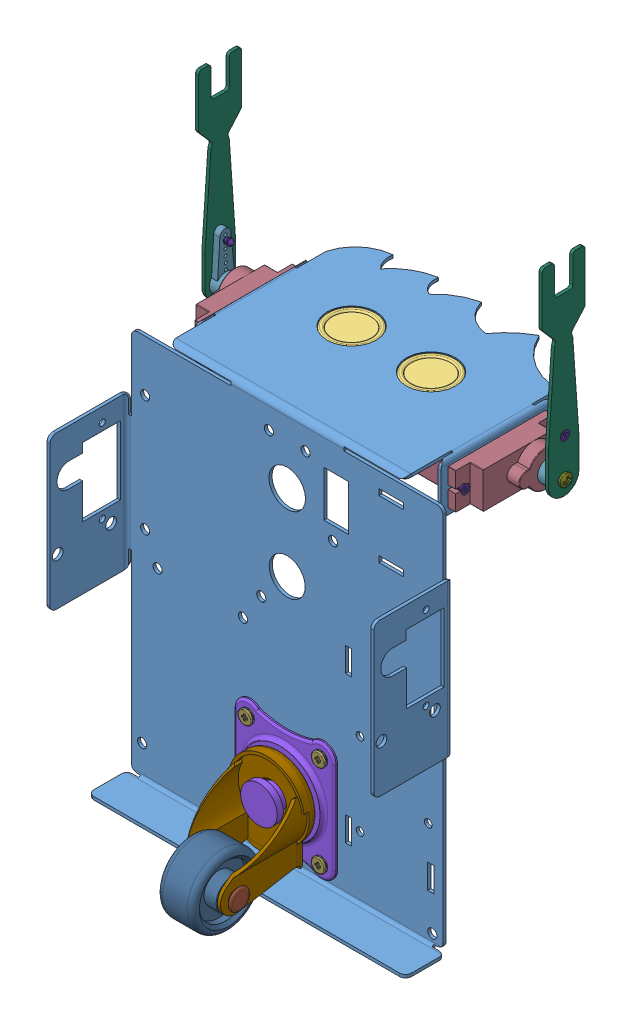
SolidWorks assembly MS_AR, configuration Predeterminado. Lengths in mm.
Overall size (116.68 188.48 99.79).
42 component instances, 17 part files, 13 mates.
Components (placement in the parent):
- DYOR_MetalSheet_Arms-1: DYOR_MetalSheet_Arms [Predeterminado] at (11.469 -59.0071 139.7994) size (107.01 129.17 87.35)
- HC-SR04 Ping Sensor-1: HC-SR04 Ping Sensor [Default] at (150.9644 -203.1957 105.6113) x (0 0 -1) z (0 1 0) size (25.18 45 18.07)
  - PCB-1: PCB [Default] at origin size (20.5 45 1.75)
  - Transducer-1: Transducer [Default] at (0 -13 13.25) x (1 0 0) z (0 -1 0) size (15.88 12 15.88)
  - Transducer-2: Transducer [Default] at (0 13 13.25) x (1 0 0) z (0 -1 0) size (15.88 12 15.88)
  - 3 Pin Header 90 Degree-1: 3 Pin Header 90 Degree [Default] at (8.4275 0 -1.25) x (-1 0 0) z (0 -1 0) size (8 7.82 10)
  - 14 Pin SMT-1: 14 Pin SMT [Default] at (-0.35 -18.5 -0.85) x (0 -1 0) z (1 0 0) size (6 1.6 8.8)
  - 14 Pin SMT-2: 14 Pin SMT [Default] at (0 -0.3826 -0.85) x (1 0 0) z (0 1 0) size (6 1.6 8.8)
  - 14 Pin SMT-3: 14 Pin SMT [Default] at (0 17.5274 -0.85) x (1 0 0) z (0 1 0) size (6 1.6 8.8)
  - Cap1 SMT-1: Cap1 SMT [Default] at (-1.755 7.4774 -0.9689) x (0 1 0) z (-1 0 0) size (4.5 1.84 1.75)
  - Cap1 SMT-2: Cap1 SMT [Default] at (6.835 7.4774 -0.9689) x (0 1 0) z (-1 0 0) size (4.5 1.84 1.75)
  - Cap1 SMT-3: Cap1 SMT [Default] at (-6.835 7.4774 -0.9689) x (0 1 0) z (-1 0 0) size (4.5 1.84 1.75)
  - Cap1 SMT-4: Cap1 SMT [Default] at (4.295 7.4774 -0.9689) x (0 1 0) z (-1 0 0) size (4.5 1.84 1.75)
  - Cap1 SMT-5: Cap1 SMT [Default] at (1.755 7.4774 -0.9689) x (0 1 0) z (-1 0 0) size (4.5 1.84 1.75)
  - Cap1 SMT-6: Cap1 SMT [Default] at (-4.295 7.4774 -0.9689) x (0 1 0) z (-1 0 0) size (4.5 1.84 1.75)
  - HC-SR04 Crystal-1: HC-SR04 Crystal [Default] at (-8.3 0 1.75) x (0 -1 0) z (0 0 1) size (10 3.5 2.7)
- CA-1: CA [Predeterminado] at (2.8545 2.6133 1.124) size (33 45.94 42.59)
  - Caster Wheel-1: Caster Wheel [Default] at (194.2283 -297.83 183.8938) x (0 1 0) z (-1 0 0) size (45.94 37.59 33)
    - caster holder-1: caster holder [Default] at (-24.0751 44.7184 29.5137) x (1 0 0) z (0 0 -1) size (39 9.27 33)
    - holder-1: holder [Default] at (-1.5751 42.9484 46.0137) x (0 0 1) z (1 0 0) size (25 28.07 31.31)
    - caster wheel-1: caster wheel [Default] at (-15.6961 19.9484 46.0137) x (0.997275 0.073773 0) z (0 0 1) size (23 23 14)
    - Part4-1: Part4 [Default] at (-15.6961 19.9484 55.0137) x (-0.978448 0.206495 0) z (0 0 -1) size (7 7 20)
  - M3x6 SelfTap Screw-1: M3x6 SelfTap Screw [Predeterminado] at (136.2146 -284.4051 140.6754) size (4.62 4.62 7)
  - M3x6 SelfTap Screw-2: M3x6 SelfTap Screw [Predeterminado] at (136.2146 -314.4051 140.6754) size (4.62 4.62 7)
  - M3x6 SelfTap Screw-3: M3x6 SelfTap Screw [Predeterminado] at (160.2146 -284.4051 140.6754) size (4.62 4.62 7)
  - M3x6 SelfTap Screw-4: M3x6 SelfTap Screw [Predeterminado] at (160.2146 -314.4051 140.6754) size (4.62 4.62 7)
- AR2-1: AR2 [Predeterminado] at (0 1.3678 1.1897) size (34.06 68.75 31.9)
  - sg90-1: sg90 [Default] at (175.3764 -204.8635 98.9775) x (0 0 1) z (0 1 0) size (31.9 29.9 11.8)
  - SG90 plastic Horn-1: SG90 plastic Horn [Default] at (204.8264 -198.9635 104.8775) x (0 0.999858 0.016879) z (0 0.016879 -0.999858) size (19.4 4 7.07)
  - Arm-1: Arm [Predeterminado] at (207.8264 -183.2019 150.0835) x (0 0 -1) z (1 0 0) size (14 67.85 1)
  - (M2_3_mm)_90116A007_METRIC 316 SS PAN HEAD PHILLIPS MACHINE SCREW-1: (M2_3_mm)_90116A007_METRIC 316 SS PAN HEAD PHILLIPS MACHINE SCREW [90116A007] at (204.8264 -198.9635 104.8775) x (0 0 -1) z (1 0 0) size (4 4 4.68)
  - M2x6 SelfTap Screw-2: M2x6 SelfTap Screw [Predeterminado] at (208.3264 -186.4635 104.8775) x (0 -0.924225 -0.381849) z (1 0 0) size (3.4 3.28 6)
  - M2x6 SelfTap Screw-4: M2x6 SelfTap Screw [Predeterminado] at (194.7764 -198.9635 123.8775) x (0 -0.924225 -0.381849) z (1 0 0) size (3.4 3.28 6)
  - M2x6 SelfTap Screw-6: M2x6 SelfTap Screw [Predeterminado] at (194.7764 -198.9635 96.5775) x (0 -0.924225 -0.381849) z (1 0 0) size (3.4 3.28 6)
- AR1-1: AR1 [Predeterminado] at (0 1.3678 1.1897) size (34.06 68.75 31.9)
  - sg90-2: sg90 [Default] at (126.818 -193.0635 98.9775) x (0 0 1) z (0 -1 0) size (31.9 29.9 11.8)
  - SG90 plastic Horn-2: SG90 plastic Horn [Default] at (97.368 -198.9635 104.8775) x (0 0.999767 0.021606) z (0 -0.021606 0.999767) size (19.4 4 7.07)
  - Arm-2: Arm [Predeterminado] at (94.368 -183.2019 59.6715) x (0 0 1) z (-1 0 0) size (14 67.85 1)
  - (M2_3_mm)_90116A007_METRIC 316 SS PAN HEAD PHILLIPS MACHINE SCREW-2: (M2_3_mm)_90116A007_METRIC 316 SS PAN HEAD PHILLIPS MACHINE SCREW [90116A007] at (97.368 -198.9635 104.8775) x (0 0 1) z (-1 0 0) size (4 4 4.68)
  - M2x6 SelfTap Screw-1: M2x6 SelfTap Screw [Predeterminado] at (93.868 -186.4635 104.8775) x (0 0.924225 0.381849) z (-1 0 0) size (3.4 3.28 6)
  - M2x6 SelfTap Screw-3: M2x6 SelfTap Screw [Predeterminado] at (107.418 -198.9635 123.8775) x (0 0.924225 0.381849) z (-1 0 0) size (3.4 3.28 6)
  - M2x6 SelfTap Screw-5: M2x6 SelfTap Screw [Predeterminado] at (107.418 -198.9635 96.5775) x (0 0.924225 0.381849) z (-1 0 0) size (3.4 3.28 6)
Mates (geometry in assembly coordinates):
- Concéntrica259: concentric: circle of DYOR_MetalSheet_Arms-1; circle of HC-SR04 Ping Sensor-1/Transducer-1
- Paralelo86: parallel: plane of DYOR_MetalSheet_Arms-1 through (114.5972 -188.9573 138.7994) normal (0 0 -1); plane of HC-SR04 Ping Sensor-1/PCB-1 through (128.4644 -201.4457 115.8613) normal (0 0 1)
- Coincidente432: coincident: plane of DYOR_MetalSheet_Arms-1 through (114.5972 -189.4457 137.6672) normal (0 1 0); plane of HC-SR04 Ping Sensor-1/Transducer-1 through (163.9644 -189.4457 97.6713) normal (0 1 0)
- Concéntrica295: concentric: circle of DYOR_MetalSheet_Arms-1; circle of ?
- Concéntrica296: concentric: circle of DYOR_MetalSheet_Arms-1; circle of ?
- Coincidente492: coincident: plane of DYOR_MetalSheet_Arms-1 through (114.5972 -188.9573 139.7994) normal (0 0 1); plane of CA-1/Caster Wheel-1/caster holder-1 through (151.0972 -251.6104 139.7994) normal (0 0 -1)
- Coincidente493: coincident: plane of AR2-1/sg90-1 through (175.3764 -191.6957 100.1672) normal (0 0 -1); plane of AR1-1/sg90-2 through (126.818 -203.4957 100.1672) normal (0 0 -1)
- Coincidente494: coincident: plane of AR2-1/sg90-1 through (175.3764 -191.6957 100.1672) normal (0 1 0); plane of AR1-1/sg90-2 through (126.818 -191.6957 100.1672) normal (0 1 0)
- Coincidente495: coincident: plane of DYOR_MetalSheet_Arms-1 through (110.918 -187.1957 137.6672) normal (-1 0 0); plane of AR1-1/sg90-2 through (110.918 -191.6957 95.4672) normal (1 0 0)
- Coincidente496: coincident: plane of DYOR_MetalSheet_Arms-1 through (191.2764 -114.1957 137.6672) normal (1 0 0); plane of AR2-1/sg90-1 through (191.2764 -203.4957 95.4672) normal (-1 0 0)
- Coincidente497: coincident: plane of DYOR_MetalSheet_Arms-1 through (190.2764 -191.6957 100.1672) normal (0 -1 0); plane of AR2-1/sg90-1 through (175.3764 -191.6957 100.1672) normal (0 1 0)
- Coincidente498: coincident: plane of DYOR_MetalSheet_Arms-1 through (190.2764 -191.6957 122.6672) normal (0 0 -1); plane of AR2-1/sg90-1 through (175.3764 -191.6957 122.6672) normal (0 0 1)
- Concéntrica297: concentric: circle of DYOR_MetalSheet_Arms-1; circle of CA-1/Caster Wheel-1/caster holder-1
